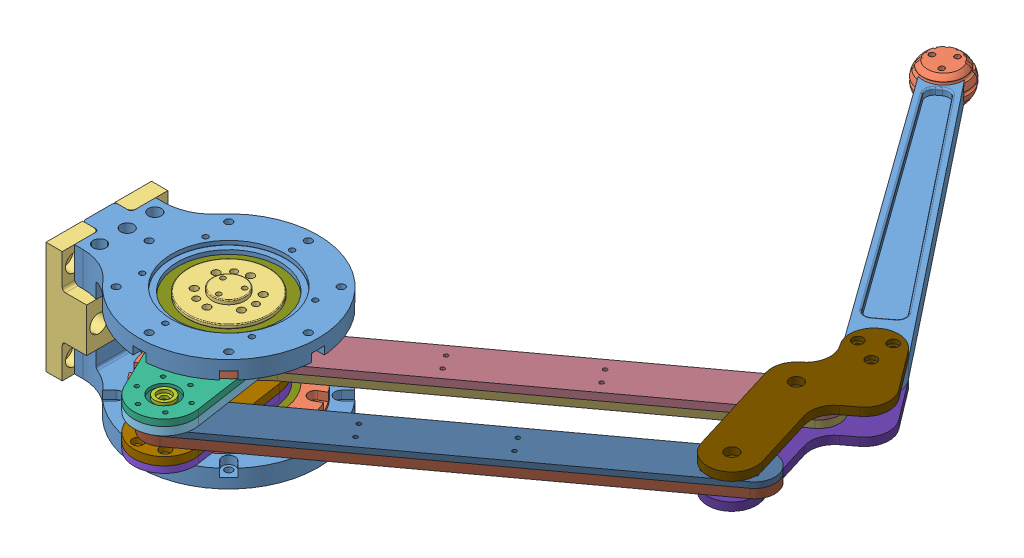
SolidWorks assembly hip_knee_assemble_v2_2nd, configuration 기본. Lengths in mm.
Overall size (344.77 69 470.26).
30 component instances, 21 part files, 69 mates.
Components (placement in the parent):
- Actuator Jig v2-1: Actuator Jig v2 [기본] at origin size (135 21 110)
- Actuator Jig Bearing Cap v2-1: Actuator Jig Bearing Cap v2 [기본] at (0 11 0) size (88 7 88)
- Load Flange v2-1: Load Flange v2 [기본] x (-0.974712 0 -0.223463) z (0.223463 0 -0.974712) size (50 17 50)
- Hip Link v2-1: Hip Link v2 [기본] at (0 52 0) x (-0.59218 0 -0.805806) z (0 1 0) size (50 50 19)
- Actuator Jig v2-2: Actuator Jig v2 [기본] at (0 69 0) x (1 0 0) z (0 0 -1) size (135 21 110)
- Actuator Jig Bearing Cap v2-2: Actuator Jig Bearing Cap v2 [기본] at (0 58 0) x (1 0 0) z (0 0 -1) size (88 7 88)
- Load Flange v2-2: Load Flange v2 [기본] at (0 69 0) x (0.401758 0 -0.915746) z (-0.915746 0 -0.401758) size (50 17 50)
- Hip Link 2 Bearing Cap_part1-1: Hip Link 2 Bearing Cap_part1 [기본] at (0 40 0) x (0.293832 0 0.955857) z (-0.955857 0 0.293832) size (106 5 55)
- Hip Link 2 Bearing Cap_part2-1: Hip Link 2 Bearing Cap_part2 [기본] at (0 39 0) x (0.293832 0 0.955857) z (-0.955857 0 0.293832) size (106 4 55)
- Bearing Cap crank v2-1: Bearing Cap crank v2 [기본] at (17.6299 24 57.3514) x (0.3598 0 0.933029) z (0.933029 0 -0.3598) size (12 4 12)
- Bearing Cap crank v2-2: Bearing Cap crank v2 [기본] at (17.6299 45 57.3514) x (0.714703 0 -0.699428) z (0.699428 0 0.714703) size (12 4 12)
- Knee Link v2_revision_part1-1: Knee Link v2_revision_part1 [기본] at (0 17 0) x (0 1 0) z (-0.293832 0 -0.955857) size (12 55 106)
- Knee Link v2_revision_part2-1: Knee Link v2_revision_part2 [기본] at (0 17 0) x (0 1 0) z (-0.293832 0 -0.955857) size (5 55 106)
- Knee Coupler v2_part1-1: Knee Coupler v2_part1 [기본] at (17.6299 34.5 57.3514) x (-0.59218 0 -0.805806) z (0.805806 0 -0.59218) size (25 9.5 285)
- Knee Coupler v2_part2-1: Knee Coupler v2_part2 [기본] at (17.6299 34.5 57.3514) x (-0.59218 0 -0.805806) z (0.805806 0 -0.59218) size (25 11.5 285)
- Knee Link1 v2_part1-1: Knee Link1 v2_part1 [기본] at (0 30 0) x (-0.59218 0 -0.805806) z (0.805806 0 -0.59218) size (35 14.5 290)
- Knee Link1 v2_part2-1: Knee Link1 v2_part2 [기본] at (0 30 0) x (-0.59218 0 -0.805806) z (0.805806 0 -0.59218) size (35 6.5 290)
- 6805ZZ-1: 6805ZZ [기본] at (0 48 0) x (1 0 0) z (0 -1 0) size (37 37 7)
- C-E6800ZZ-1: C-E6800ZZ [기본] at (17.6299 47 57.3514) x (1 0 0) z (0 -1 0) size (19 19 5)
- 6805ZZ-2: 6805ZZ [기본] at (0 27 0) x (0.995685 0 0.092795) z (0 -1 0) size (37 37 7)
- C-E6800ZZ-2: C-E6800ZZ [기본] at (17.6299 27 57.3514) x (-0.867757 0 0.49699) z (0 -1 0) size (19 19 5)
- C-E6800ZZ-3: C-E6800ZZ [기본] at (201.4514 37 -148.045) x (1 0 0) z (0 -1 0) size (19 19 5)
- C-E6800ZZ-4: C-E6800ZZ [기본] at (219.0813 37 -90.6936) x (0.999999 0 0.00156) z (0 -1 0) size (19 19 5)
- C-SE6909ZZ-1: C-SE6909ZZ [기본] at (0 17 0) x (0.999622 0 0.027492) z (0 -1 0) size (68 68 12)
- C-SE6909ZZ-2: C-SE6909ZZ [기본] at (0 64 0) x (0.999622 0 0.027492) z (0 -1 0) size (68 68 12)
- Knee Link4 v2-1: Knee Link4 v2 [기본] at (201.4514 24 -148.045) x (-0.955857 0 0.293832) z (-0.293832 0 -0.955857) size (58.19 8 128.45)
- Knee Link4-2 v2-1: Knee Link4-2 v2 [기본] at (201.4514 45 -148.045) x (0.955857 0 -0.293832) z (-0.293832 0 -0.955857) size (58.19 13 128.45)
- Shank link-1: Shank link [기본] at (207.2919 40 -190.0675) x (0.603034 0 0.797716) z (0.797716 0 -0.603034) size (245 11.07 30.07)
- Tire-1: Tire [기본] at (74.6244 34.5 -365.5649) x (0 -1 0) z (0.797716 0 -0.603034) size (20 28.11 30.82)
- abduction_zig-1: abduction_zig [기본] at (-80 34.5 0) x (0 -1 0) z (1 0 0) size (69 65 25)
Mates (geometry in assembly coordinates):
- 동심3: concentric anti-aligned: cylinder of Load Flange v2-1 through (0 17 0) axis (0 -1 0) radius 22.5; cylinder of C-SE6909ZZ-1 through (0 5 0) axis (0 1 0) radius 22.5
- 일치1: coincident aligned: plane of Actuator Jig v2-1 through (0 0 0) normal (0 -1 0); plane of Load Flange v2-1 through (0 0 0) normal (0 -1 0)
- 동심4: concentric anti-aligned: cylinder of Load Flange v2-1 through (-6.691 12 2.0568) axis (0 1 0) radius 1.5; cylinder of Knee Link v2_revision_part1-1 through (-6.691 12 2.0568) axis (0 -1 0) radius 1.5
- 동심6: concentric anti-aligned: cylinder of Load Flange v2-1 through (5.1268 12 4.7662) axis (0 1 0) radius 1.5; cylinder of Knee Link v2_revision_part1-1 through (5.1268 12 4.7662) axis (0 -1 0) radius 1.5
- 일치2: coincident anti-aligned: plane of Load Flange v2-1 through (0 17 0) normal (0 1 0); plane of Knee Link v2_revision_part1-1 through (0 17 0) normal (0 -1 0)
- 동심7: concentric anti-aligned: cylinder of Knee Link v2_revision_part1-1 through (0 27 0) axis (0 -1 0) radius 18.5; cylinder of 6805ZZ-2 through (0 20 0) axis (0 1 0) radius 18.5
- 일치3: coincident anti-aligned: plane of Knee Link v2_revision_part1-1 through (0 20 0) normal (0 1 0); plane of 6805ZZ-2 through (0 20 0) normal (0 -1 0)
- 동심8: concentric aligned: cylinder of Knee Link v2_revision_part1-1 through (17.6299 22 57.3514) axis (0 1 0) radius 9.5; cylinder of C-E6800ZZ-2 through (17.6299 22 57.3514) axis (0 1 0) radius 9.5
- 일치4: coincident anti-aligned: plane of Knee Link v2_revision_part1-1 through (17.6299 22 57.3514) normal (0 1 0); plane of C-E6800ZZ-2 through (17.6299 22 57.3514) normal (0 -1 0)
- 동심9: concentric aligned: cylinder of Knee Link v2_revision_part1-1 through (4.7258 24 61.3182) axis (0 1 0) radius 1.25; cylinder of Knee Link v2_revision_part2-1 through (4.7258 29 61.3182) axis (0 1 0) radius 3.25
- 동심10: concentric aligned: cylinder of Knee Link v2_revision_part1-1 through (14.6132 24 70.51) axis (0 1 0) radius 1.25; cylinder of Knee Link v2_revision_part2-1 through (14.6132 29 70.51) axis (0 1 0) radius 3.25
- 일치5: coincident anti-aligned: plane of Knee Link v2_revision_part1-1 through (355.5527 24 1053.0102) normal (0 1 0); plane of Knee Link v2_revision_part2-1 through (355.5527 24 1053.0102) normal (0 -1 0)
- 동심11: concentric aligned: cylinder of Actuator Jig v2-2 through (33.775 58 19.5) axis (0 -1 0) radius 1.65; cylinder of Actuator Jig Bearing Cap v2-2 through (33.775 51 19.5) axis (0 -1 0) radius 4
- 동심12: concentric aligned: cylinder of Actuator Jig v2-2 through (33.775 58 -19.5) axis (0 -1 0) radius 1.65; cylinder of Actuator Jig Bearing Cap v2-2 through (33.775 51 -19.5) axis (0 -1 0) radius 2.25
- 일치6: coincident anti-aligned: plane of Actuator Jig v2-2 through (0 58 0) normal (0 -1 0); plane of Actuator Jig Bearing Cap v2-2 through (0 58 0) normal (0 1 0)
- 동심13: concentric aligned: cylinder of Actuator Jig v2-2 through (0 58 0) axis (0 1 0) radius 34; cylinder of C-SE6909ZZ-2 through (0 52 0) axis (0 1 0) radius 34
- 일치7: coincident anti-aligned: plane of Actuator Jig Bearing Cap v2-2 through (0 52 0) normal (0 1 0); plane of C-SE6909ZZ-2 through (0 52 0) normal (0 -1 0)
- 동심14: concentric aligned: cylinder of Load Flange v2-2 through (0 52 0) axis (0 1 0) radius 22.5; cylinder of C-SE6909ZZ-2 through (0 52 0) axis (0 1 0) radius 22.5
- 일치8: coincident aligned: plane of Actuator Jig v2-2 through (0 69 0) normal (0 1 0); plane of Load Flange v2-2 through (0 69 0) normal (0 1 0)
- 동심17: concentric aligned: cylinder of Hip Link 2 Bearing Cap_part1-1 through (-21.5068 40 6.6112) axis (0 -1 0) radius 3.25; cylinder of Hip Link 2 Bearing Cap_part2-1 through (-21.5068 45 6.6112) axis (0 -1 0) radius 1.25
- 동심18: concentric aligned: cylinder of Hip Link 2 Bearing Cap_part1-1 through (-5.0279 40 21.931) axis (0 -1 0) radius 3.25; cylinder of Hip Link 2 Bearing Cap_part2-1 through (-5.0279 45 21.931) axis (0 -1 0) radius 1.25
- 일치10: coincident anti-aligned: plane of Hip Link 2 Bearing Cap_part1-1 through (-358.7766 45 -1052.0191) normal (0 1 0); plane of Hip Link 2 Bearing Cap_part2-1 through (-358.7766 45 -1052.0191) normal (0 -1 0)
- 동심19: concentric anti-aligned: cylinder of Hip Link 2 Bearing Cap_part1-1 through (0 49 0) axis (0 -1 0) radius 18.5; cylinder of 6805ZZ-1 through (0 41 0) axis (0 1 0) radius 18.5
- 일치11: coincident anti-aligned: plane of Hip Link 2 Bearing Cap_part1-1 through (0 41 0) normal (0 1 0); plane of 6805ZZ-1 through (0 41 0) normal (0 -1 0)
- 동심20: concentric anti-aligned: cylinder of Hip Link 2 Bearing Cap_part1-1 through (17.6299 47 57.3514) axis (0 -1 0) radius 9.5; cylinder of C-E6800ZZ-1 through (17.6299 42 57.3514) axis (0 1 0) radius 9.5
- 일치12: coincident anti-aligned: plane of Hip Link 2 Bearing Cap_part1-1 through (17.6299 42 57.3514) normal (0 1 0); plane of C-E6800ZZ-1 through (17.6299 42 57.3514) normal (0 -1 0)
- 동심21: concentric aligned: cylinder of Hip Link v2-1 through (0 41 0) axis (0 1 0) radius 12.5; cylinder of 6805ZZ-1 through (0 41 0) axis (0 1 0) radius 12.5
- 일치13: coincident anti-aligned: plane of Hip Link v2-1 through (0 48 0) normal (0 -1 0); plane of 6805ZZ-1 through (0 48 0) normal (0 1 0)
- 동심22: concentric aligned: cylinder of Knee Link1 v2_part1-1 through (196.0277 30 -135.6825) axis (0 -1 0) radius 1.6; cylinder of Knee Link1 v2_part2-1 through (196.0277 34.5 -135.6825) axis (0 -1 0) radius 1.25
- 동심23: concentric aligned: cylinder of Knee Link1 v2_part1-1 through (188.0332 30 -146.5608) axis (0 -1 0) radius 1.6; cylinder of Knee Link1 v2_part2-1 through (188.0332 34.5 -146.5608) axis (0 -1 0) radius 1.25
- 일치14: coincident anti-aligned: plane of Knee Link1 v2_part1-1 through (-876.0335 34.5 684.0609) normal (0 1 0); plane of Knee Link1 v2_part2-1 through (-876.0335 34.5 684.0609) normal (0 -1 0)
- 동심24: concentric aligned: cylinder of Knee Link1 v2_part1-1 through (201.4514 27 -148.045) axis (0 1 0) radius 9.5; cylinder of C-E6800ZZ-3 through (201.4514 32 -148.045) axis (0 1 0) radius 9.5
- 일치15: coincident anti-aligned: plane of Knee Link1 v2_part1-1 through (201.4514 32 -148.045) normal (0 1 0); plane of C-E6800ZZ-3 through (201.4514 32 -148.045) normal (0 -1 0)
- 동심29: concentric anti-aligned: cylinder of Hip Link v2-1 through (-6.4102 57 -2.8123) axis (0 1 0) radius 1.5; cylinder of Load Flange v2-2 through (-6.4102 57 -2.8123) axis (0 -1 0) radius 1.5
- 동심30: concentric anti-aligned: cylinder of Hip Link v2-1 through (5.6406 57 -4.1453) axis (0 1 0) radius 1.5; cylinder of Load Flange v2-2 through (5.6406 57 -4.1453) axis (0 -1 0) radius 1.5
- 일치17: coincident anti-aligned: plane of Hip Link v2-1 through (0 52 0) normal (0 1 0); plane of Load Flange v2-2 through (0 52 0) normal (0 -1 0)
- 동심31: concentric anti-aligned: cylinder of Hip Link v2-1 through (-6.8493 38 5.0335) axis (0 -1 0) radius 1.5; cylinder of Knee Link1 v2_part2-1 through (-6.8493 38 5.0335) axis (0 1 0) radius 1.5
- 동심32: concentric anti-aligned: cylinder of Hip Link v2-1 through (-0.9345 38 -8.4485) axis (0 -1 0) radius 1.5; cylinder of Knee Link1 v2_part2-1 through (-0.9345 38 -8.4485) axis (0 1 0) radius 1.5
- 일치18: coincident anti-aligned: plane of Hip Link v2-1 through (0 41 0) normal (0 -1 0); plane of Knee Link1 v2_part2-1 through (0 41 0) normal (0 1 0)
- 동심33: concentric aligned: cylinder of Knee Coupler v2_part1-1 through (17.6299 24 57.3514) axis (0 1 0) radius 5; cylinder of C-E6800ZZ-1 through (17.6299 42 57.3514) axis (0 1 0) radius 5
- 일치19: coincident anti-aligned: plane of Knee Coupler v2_part1-1 through (17.6299 42 57.3514) normal (0 1 0); plane of C-E6800ZZ-1 through (17.6299 42 57.3514) normal (0 -1 0)
- 동심34: concentric aligned: cylinder of Knee Coupler v2_part2-1 through (17.6299 24 57.3514) axis (0 1 0) radius 5; cylinder of C-E6800ZZ-2 through (17.6299 22 57.3514) axis (0 1 0) radius 5
- 일치20: coincident anti-aligned: plane of Knee Coupler v2_part2-1 through (17.6299 27 57.3514) normal (0 -1 0); plane of C-E6800ZZ-2 through (17.6299 27 57.3514) normal (0 1 0)
- 동심36: concentric anti-aligned: cylinder of Knee Coupler v2_part2-1 through (219.0813 37 -90.6936) axis (0 -1 0) radius 9.5; cylinder of C-E6800ZZ-4 through (219.0813 32 -90.6936) axis (0 1 0) radius 9.5
- 일치21: coincident anti-aligned: plane of Knee Coupler v2_part2-1 through (219.0813 32 -90.6936) normal (0 1 0); plane of C-E6800ZZ-4 through (219.0813 32 -90.6936) normal (0 -1 0)
- 동심37: concentric anti-aligned: cylinder of Knee Coupler v2_part1-1 through (219.0813 37 -90.6936) axis (0 -1 0) radius 9.5; cylinder of C-E6800ZZ-4 through (219.0813 32 -90.6936) axis (0 1 0) radius 9.5
- 일치22: coincident anti-aligned: plane of Knee Coupler v2_part1-1 through (219.0813 37 -90.6936) normal (0 -1 0); plane of C-E6800ZZ-4 through (219.0813 37 -90.6936) normal (0 1 0)
- 동심38: concentric aligned: cylinder of Knee Coupler v2_part1-1 through (17.6299 24 57.3514) axis (0 -1 0) radius 1.65; cylinder of Knee Coupler v2_part2-1 through (17.6299 24 57.3514) axis (0 -1 0) radius 1.65
- 일치23: coincident aligned: plane of Actuator Jig v2-1 through (-70 2.5 55) normal (-1 0 0); plane of Actuator Jig v2-2 through (-70 66.5 -55) normal (-1 0 0)
- 동심39: concentric aligned: cylinder of Knee Link1 v2_part1-1 through (0 20 0) axis (0 1 0) radius 12.5; cylinder of 6805ZZ-2 through (0 20 0) axis (0 1 0) radius 12.5
- 동심41: concentric anti-aligned: cylinder of Bearing Cap crank v2-2 through (17.6299 47 57.3514) axis (0 -1 0) radius 5; cylinder of C-E6800ZZ-1 through (17.6299 42 57.3514) axis (0 1 0) radius 5
- 일치24: coincident anti-aligned: plane of Bearing Cap crank v2-2 through (17.6299 47 57.3514) normal (0 -1 0); plane of C-E6800ZZ-1 through (17.6299 47 57.3514) normal (0 1 0)
- 동심42: concentric aligned: cylinder of Bearing Cap crank v2-1 through (17.6299 22 57.3514) axis (0 1 0) radius 5; cylinder of C-E6800ZZ-2 through (17.6299 22 57.3514) axis (0 1 0) radius 5
- 일치25: coincident anti-aligned: plane of Bearing Cap crank v2-1 through (17.6299 22 57.3514) normal (0 1 0); plane of C-E6800ZZ-2 through (17.6299 22 57.3514) normal (0 -1 0)
- 동심43: concentric aligned: cylinder of C-E6800ZZ-4 through (219.0813 32 -90.6936) axis (0 1 0) radius 5; cylinder of Knee Link4-2 v2-1 through (219.0813 45 -90.6936) axis (0 1 0) radius 4
- 동심44: concentric aligned: cylinder of Knee Link1 v2_part2-1 through (201.4514 37 -148.045) axis (0 1 0) radius 8.5; cylinder of Knee Link4-2 v2-1 through (201.4514 32 -148.045) axis (0 1 0) radius 5
- 일치26: coincident anti-aligned: plane of C-E6800ZZ-4 through (219.0813 37 -90.6936) normal (0 1 0); plane of Knee Link4-2 v2-1 through (219.0813 37 -90.6936) normal (0 -1 0)
- 동심45: concentric aligned: cylinder of Knee Coupler v2_part2-1 through (219.0813 32 -90.6936) axis (0 -1 0) radius 8.5; cylinder of Knee Link4 v2-1 through (219.0813 32 -90.6936) axis (0 -1 0) radius 6.25
- 동심46: concentric aligned: cylinder of Knee Link1 v2_part1-1 through (201.4514 32 -148.045) axis (0 -1 0) radius 8.5; cylinder of Knee Link4 v2-1 through (201.4514 32 -148.045) axis (0 -1 0) radius 6.25
- 일치27: coincident anti-aligned: plane of C-E6800ZZ-4 through (219.0813 32 -90.6936) normal (0 -1 0); plane of Knee Link4 v2-1 through (219.0813 32 -90.6936) normal (0 1 0)
- 동심47: concentric aligned: cylinder of Knee Link4 v2-1 through (212.7192 24 -182.8881) axis (0 -1 0) radius 1.7; cylinder of Shank link-1 through (212.7192 29 -182.8881) axis (0 -1 0) radius 1.25
- 동심48: concentric aligned: cylinder of Knee Link4 v2-1 through (198.3606 24 -188.957) axis (0 -1 0) radius 3.25; cylinder of Shank link-1 through (198.3606 29 -188.957) axis (0 -1 0) radius 1.25
- 일치28: coincident anti-aligned: plane of Knee Link4 v2-1 through (201.4514 29 -148.045) normal (0 1 0); plane of Shank link-1 through (207.2919 29 -190.0675) normal (0 -1 0)
- 동심49: concentric anti-aligned: cylinder of Shank link-1 through (77.155 29 -371.5521) axis (0 -1 0) radius 1.25; cylinder of Tire-1 through (77.155 44.5 -371.5521) axis (0 1 0) radius 1.7
- 동심50: concentric anti-aligned: cylinder of Shank link-1 through (78.5441 29 -360.3798) axis (0 -1 0) radius 1.25; cylinder of Tire-1 through (78.5441 44.5 -360.3798) axis (0 1 0) radius 1.7
- 일치29: coincident anti-aligned: plane of Shank link-1 through (207.2919 29 -190.0675) normal (0 -1 0); plane of Tire-1 through (74.6244 29 -365.5649) normal (0 1 0)
- 동심51: concentric aligned: cylinder of Actuator Jig v2-2 through (-62.5 69 -17) axis (0 1 0) radius 4; cylinder of abduction_zig-1 through (-62.5 48 -17) axis (0 1 0) radius 1.65
- 동심52: concentric aligned: cylinder of Actuator Jig v2-2 through (-62.5 69 0) axis (0 1 0) radius 4; cylinder of abduction_zig-1 through (-62.5 48 0) axis (0 1 0) radius 1.65
- 일치30: coincident anti-aligned: plane of Actuator Jig v2-2 through (0 48 0) normal (0 -1 0); plane of abduction_zig-1 through (-55 48 32.5) normal (0 1 0)
